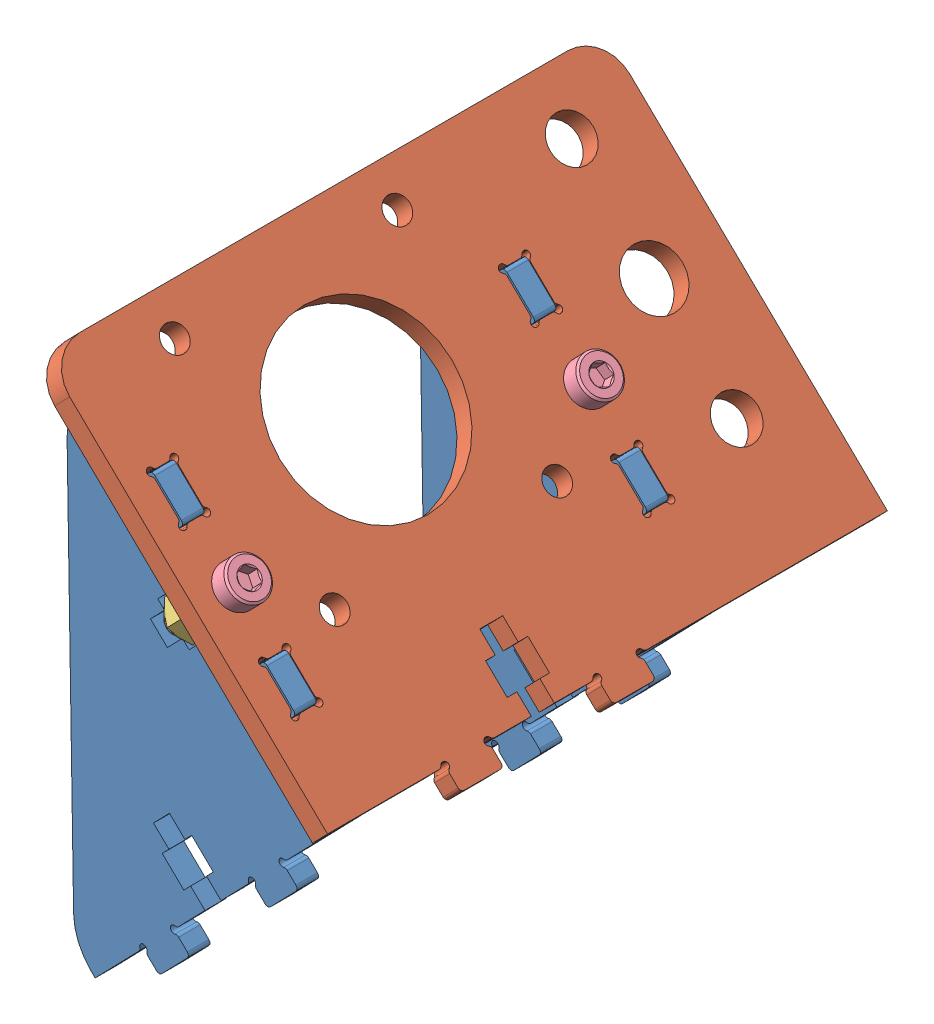
SolidWorks assembly Z-Motor-mount-left-side, configuration Default. Lengths in mm.
Overall size (74 77.94 78).
7 component instances, 4 part files, 16 mates.
Components (placement in the parent):
- Z-Motor-Mount-side-1: Z-Motor-Mount-side [Default] at (-703.3107 -160.2818 527.3343) x (0.718302 -0.695732 0) z (0 0 1) size (52.33 52.33 3)
- Z-Motor-Mount-top-v2-beta-1: Z-Motor-Mount-top-v2-beta [Default] at (968.268 -300.6657 161.941) x (0 0 1) z (0.718302 -0.695732 0) size (78 3 58)
- Z-Motor-Mount-side-2: Z-Motor-Mount-side [Default] at (-703.3153 -160.2773 478.2944) x (0.718302 -0.695732 0) z (0 0 1) size (52.33 52.33 3)
- 90576A102_ZINC-PLATED CLASS 8 STL NYLON-INSERT LOCKNUT-1: 90576A102_ZINC-PLATED CLASS 8 STL NYLON-INSERT LOCKNUT [90576A102] at (211.5657 424.1853 528.8343) x (0.359151 -0.347866 -0.866025) z (-0.622068 0.602521 -0.5) size (5.5 4.1 6.35)
- 90576A102_ZINC-PLATED CLASS 8 STL NYLON-INSERT LOCKNUT-2: 90576A102_ZINC-PLATED CLASS 8 STL NYLON-INSERT LOCKNUT [90576A102] at (211.5606 424.1902 479.7943) x (-0.718302 0.695732 0) z (0 0 1) size (5.5 4.1 6.35)
- 91292A114_TYPE 18-8 SS SOCKET HEAD CAP SCREW-1: 91292A114_TYPE 18-8 SS SOCKET HEAD CAP SCREW [91292A114] at (207.247 419.7367 479.7943) x (0.077249 -0.074822 0.9942) z (-0.695732 -0.718302 0) size (5.5 5.5 15.58)
- 91292A114_TYPE 18-8 SS SOCKET HEAD CAP SCREW-2: 91292A114_TYPE 18-8 SS SOCKET HEAD CAP SCREW [91292A114] at (207.2521 419.7318 528.8343) x (0.515957 -0.499745 0.695732) z (-0.695732 -0.718302 0) size (5.5 5.5 15.58)
Mates (geometry in assembly coordinates):
- Width1: width anti-aligned: plane of Z-Motor-Mount-side-2 through (208.6672 384.322 481.2944) normal (0 0 1); plane of Z-Motor-Mount-side-2 through (208.6672 384.322 478.2944) normal (0 0 -1); plane of Z-Motor-Mount-top-v2-beta-1 through (207.3057 432.2094 481.4443) normal (0 0 -1); plane of Z-Motor-Mount-top-v2-beta-1 through (204.0964 435.3179 478.1444) normal (0 0 1)
- Coincident1: coincident anti-aligned: plane of Z-Motor-Mount-top-v2-beta-1 through (196.0246 443.1361 461.3143) normal (-0.695732 -0.718302 0); plane of Z-Motor-Mount-side-2 through (218.4769 421.3893 481.2944) normal (0.695732 0.718302 0)
- Width3: width anti-aligned: plane of Z-Motor-Mount-side-1 through (208.6717 384.3176 530.3343) normal (0 0 1); plane of Z-Motor-Mount-side-1 through (208.6717 384.3176 527.3343) normal (0 0 -1); plane of Z-Motor-Mount-top-v2-beta-1 through (222.9355 417.0707 530.4843) normal (0 0 -1); plane of Z-Motor-Mount-top-v2-beta-1 through (219.7262 420.1792 527.1844) normal (0 0 1)
- Width4: width anti-aligned: plane of Z-Motor-Mount-side-1 through (220.9045 422.6093 530.3343) normal (-0.718302 0.695732 0); plane of Z-Motor-Mount-side-1 through (224.1602 417.1216 530.3343) normal (0.718302 -0.695732 0); plane of Z-Motor-Mount-top-v2-beta-1 through (219.1041 420.7817 529.6183) normal (0.718302 -0.695732 0); plane of Z-Motor-Mount-top-v2-beta-1 through (223.5576 416.4682 528.0504) normal (-0.718302 0.695732 0)
- Coincident3: coincident anti-aligned: plane of Z-Motor-Mount-side-1 through (218.4815 421.3849 530.3343) normal (0.695732 0.718302 0); plane of Z-Motor-Mount-top-v2-beta-1 through (196.0246 443.1361 461.3143) normal (-0.695732 -0.718302 0)
- Coincident4: coincident anti-aligned: plane of Z-Motor-Mount-side-1 through (212.7495 423.0387 530.3343) normal (-0.695732 -0.718302 0); plane of 90576A102_ZINC-PLATED CLASS 8 STL NYLON-INSERT LOCKNUT-1 through (213.541 422.272 527.2466) normal (0.695732 0.718302 0)
- Concentric1: concentric aligned: cylinder of Z-Motor-Mount-top-v2-beta-1 through (213.5137 426.1965 528.8343) axis (0.695732 0.718302 0) radius 1.6; circle of 90576A102_ZINC-PLATED CLASS 8 STL NYLON-INSERT LOCKNUT-1
- Parallel1: parallel aligned: plane of Z-Motor-Mount-side-1 through (213.6892 422.1285 530.3343) normal (-0.718302 0.695732 0); plane of 90576A102_ZINC-PLATED CLASS 8 STL NYLON-INSERT LOCKNUT-1 through (206.8074 423.2253 530.4221) normal (-0.718302 0.695732 0)
- Coincident5: coincident anti-aligned: plane of Z-Motor-Mount-side-2 through (212.7449 423.0431 481.2944) normal (-0.695732 -0.718302 0); plane of 90576A102_ZINC-PLATED CLASS 8 STL NYLON-INSERT LOCKNUT-2 through (209.5853 426.1035 478.2066) normal (0.695732 0.718302 0)
- Concentric2: concentric aligned: cylinder of Z-Motor-Mount-top-v2-beta-1 through (213.5086 426.2014 479.7943) axis (0.695732 0.718302 0) radius 1.6; circle of 90576A102_ZINC-PLATED CLASS 8 STL NYLON-INSERT LOCKNUT-2
- Parallel2: parallel aligned: plane of Z-Motor-Mount-side-2 through (213.6846 422.1329 481.2944) normal (-0.718302 0.695732 0); plane of 90576A102_ZINC-PLATED CLASS 8 STL NYLON-INSERT LOCKNUT-2 through (206.8023 423.2302 481.3821) normal (-0.718302 0.695732 0)
- Coincident6: coincident anti-aligned: plane of Z-Motor-Mount-top-v2-beta-1 through (198.1118 445.291 461.3143) normal (0.695732 0.718302 0); plane of 91292A114_TYPE 18-8 SS SOCKET HEAD CAP SCREW-1 through (215.5958 428.3563 479.7943) normal (-0.695732 -0.718302 0)
- Concentric3: concentric anti-aligned: cylinder of Z-Motor-Mount-top-v2-beta-1 through (213.5086 426.2014 479.7943) axis (0.695732 0.718302 0) radius 1.6; cylinder of 91292A114_TYPE 18-8 SS SOCKET HEAD CAP SCREW-1 through (217.683 430.5112 479.7943) axis (-0.695732 -0.718302 0) radius 2.75
- Coincident7: coincident anti-aligned: plane of Z-Motor-Mount-top-v2-beta-1 through (198.1118 445.291 461.3143) normal (0.695732 0.718302 0); plane of 91292A114_TYPE 18-8 SS SOCKET HEAD CAP SCREW-2 through (215.6009 428.3514 528.8343) normal (-0.695732 -0.718302 0)
- Concentric4: concentric anti-aligned: cylinder of Z-Motor-Mount-top-v2-beta-1 through (213.5137 426.1965 528.8343) axis (0.695732 0.718302 0) radius 1.6; cylinder of 91292A114_TYPE 18-8 SS SOCKET HEAD CAP SCREW-2 through (217.6881 430.5063 528.8343) axis (-0.695732 -0.718302 0) radius 2.75
- Width5: width anti-aligned: plane of Z-Motor-Mount-side-2 through (208.5304 432.2603 481.2944) normal (0.718302 -0.695732 0); plane of Z-Motor-Mount-side-2 through (205.2747 437.748 481.2944) normal (-0.718302 0.695732 0); plane of Z-Motor-Mount-top-v2-beta-1 through (207.9278 431.6069 479.0104) normal (-0.718302 0.695732 0); plane of Z-Motor-Mount-top-v2-beta-1 through (203.4743 435.9204 480.5783) normal (0.718302 -0.695732 0)
